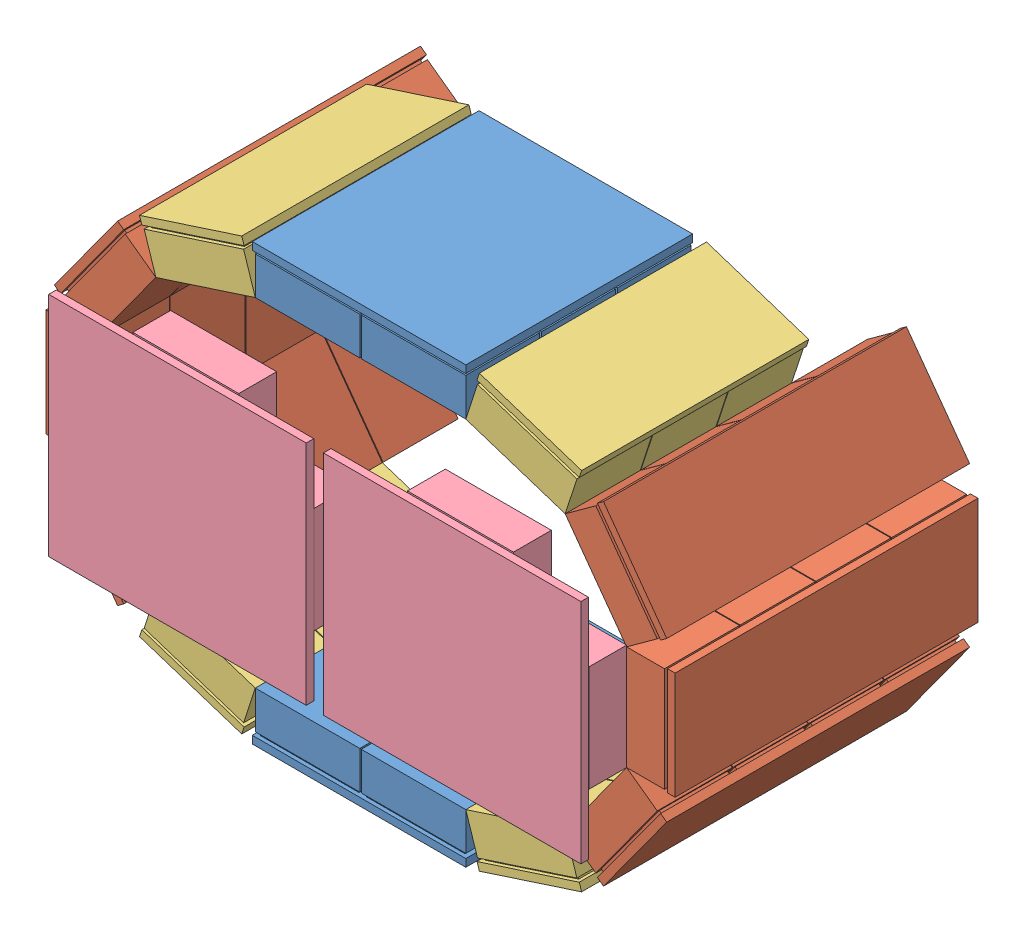
SolidWorks assembly Detector1n2_2, configuration Default. Lengths in mm.
Overall size (495.24 340.33 230.2).
16 component instances, 4 part files, 13 mates.
Components (placement in the parent):
- top_bottomDetector2-1: top_bottomDetector2 [Default] at (5.3043 60.2155 74.3483) size (141 32 149.74)
- CshapedDetector2-1: CshapedDetector2 [Default] at (104.3454 -76.5763 -85.899) x (0.951057 0.309017 0) z (0 0 1) size (177.89 270.84 200)
  - 1Detector-2: 1Detector [Default] at (173.0714 153.2337 184.2598) x (0.809017 0.587785 0) z (0 0 1) size (71 32 200)
  - 1Detector-4: 1Detector [Default] at (223.2683 222.3237 184.2598) x (0.309017 0.951057 0) z (0 0 1) size (71 32 200)
  - 1Detector-5: 1Detector [Default] at (223.2683 307.7237 184.2598) x (-0.309017 0.951057 0) z (0 0 1) size (71 32 200)
  - 1Detector_3modules-1: 1Detector_3modules [Default] at (91.8512 126.8436 209.2598) size (71 32 150)
  - 1Detector_3modules-2: 1Detector_3modules [Default] at (173.0714 376.8138 209.2598) x (-0.809017 0.587785 0) z (0 0 1) size (71 32 150)
- CshapedDetector2-2: CshapedDetector2 [Default] at (-23.7368 484.2959 -85.899) x (-0.951057 -0.309017 0) z (0 0 1) size (177.89 270.84 200)
  - 1Detector-2: 1Detector [Default] at (173.0714 153.2337 184.2598) x (0.809017 0.587785 0) z (0 0 1) size (71 32 200)
  - 1Detector-4: 1Detector [Default] at (223.2683 222.3237 184.2598) x (0.309017 0.951057 0) z (0 0 1) size (71 32 200)
  - 1Detector-5: 1Detector [Default] at (223.2683 307.7237 184.2598) x (-0.309017 0.951057 0) z (0 0 1) size (71 32 200)
  - 1Detector_3modules-1: 1Detector_3modules [Default] at (91.8512 126.8436 209.2598) size (71 32 150)
  - 1Detector_3modules-2: 1Detector_3modules [Default] at (173.0714 376.8138 209.2598) x (-0.809017 0.587785 0) z (0 0 1) size (71 32 150)
- top_bottomDetector2-2: top_bottomDetector2 [Default] at (75.3043 347.5042 74.3483) x (-1 0 0) z (0 0 1) size (141 32 149.74)
- Detector2-1: Detector2 [Default] at (-50.3758 204.3598 228.5608) x (1 0 0) z (0 1 0) size (170 30.5 151.04)
- Detector2-2: Detector2 [Default] at (130.9844 204.3598 228.5608) x (1 0 0) z (0 1 0) size (170 30.5 151.04)
Mates (geometry in assembly coordinates):
- Coincident2: coincident anti-aligned: line of top_bottomDetector2-1 through (109.8043 92.2155 198.3608) axis (0 0 -1); line of CshapedDetector2-1/1Detector_3modules-1 through (109.8043 92.2155 148.8608) axis (0 0 1)
- Angle1: planar angle = 3.455752 rad anti-aligned: line of top_bottomDetector2-1 through (40.8043 92.2155 198.3608) axis (1 0 0); line of CshapedDetector2-1/1Detector_3modules-1 through (109.8043 92.2155 198.3608) axis (0.951057 0.309017 0)
- Coincident4: coincident: point of top_bottomDetector2-1; point of CshapedDetector2-1/1Detector_3modules-1
- Coincident5: coincident anti-aligned: line of top_bottomDetector2-1 through (-29.1957 92.2155 149.6059) axis (0 0 1); line of CshapedDetector2-2/1Detector_3modules-2 through (-29.1957 92.2155 198.3608) axis (0 0 -1)
- Angle2: planar angle = 3.455752 rad anti-aligned: line of CshapedDetector2-2/1Detector_3modules-2 through (-94.8186 113.5376 198.3608) axis (0.951057 -0.309017 0); line of top_bottomDetector2-1 through (-29.1957 92.2155 198.3608) axis (1 0 0)
- Coincident7: coincident: point of top_bottomDetector2-1; point of CshapedDetector2-2/1Detector_3modules-2
- Coincident8: coincident: line of top_bottomDetector2-2 through (-29.1957 315.5042 198.3608) axis (0 0 -1); line of CshapedDetector2-2/1Detector_3modules-1 through (-29.1957 315.5042 148.8608) axis (0 0 1)
- Coincident11: coincident: line of CshapedDetector2-1/1Detector_3modules-2 through (109.8043 315.5042 198.3608) axis (0 0 -1); line of top_bottomDetector2-2 through (109.8043 315.5042 149.6059) axis (0 0 1)
- Coincident12: coincident: point of CshapedDetector2-2/1Detector_3modules-1; point of top_bottomDetector2-2
- Coincident13: coincident: line of CshapedDetector2-2/1Detector-4 through (-135.3758 238.3598 198.3608) axis (0 -1 0); line of Detector2-1 through (-135.3758 169.3598 198.3608) axis (0 1 0)
- Coincident14: coincident: point of CshapedDetector2-2/1Detector-5; point of Detector2-1
- Coincident15: coincident: line of CshapedDetector2-1/1Detector-4 through (215.9844 169.3598 198.3608) axis (0 1 0); line of Detector2-2 through (215.9844 239.3598 198.3608) axis (0 -1 0)
- Coincident16: coincident: point of CshapedDetector2-1/1Detector-2; point of Detector2-2
